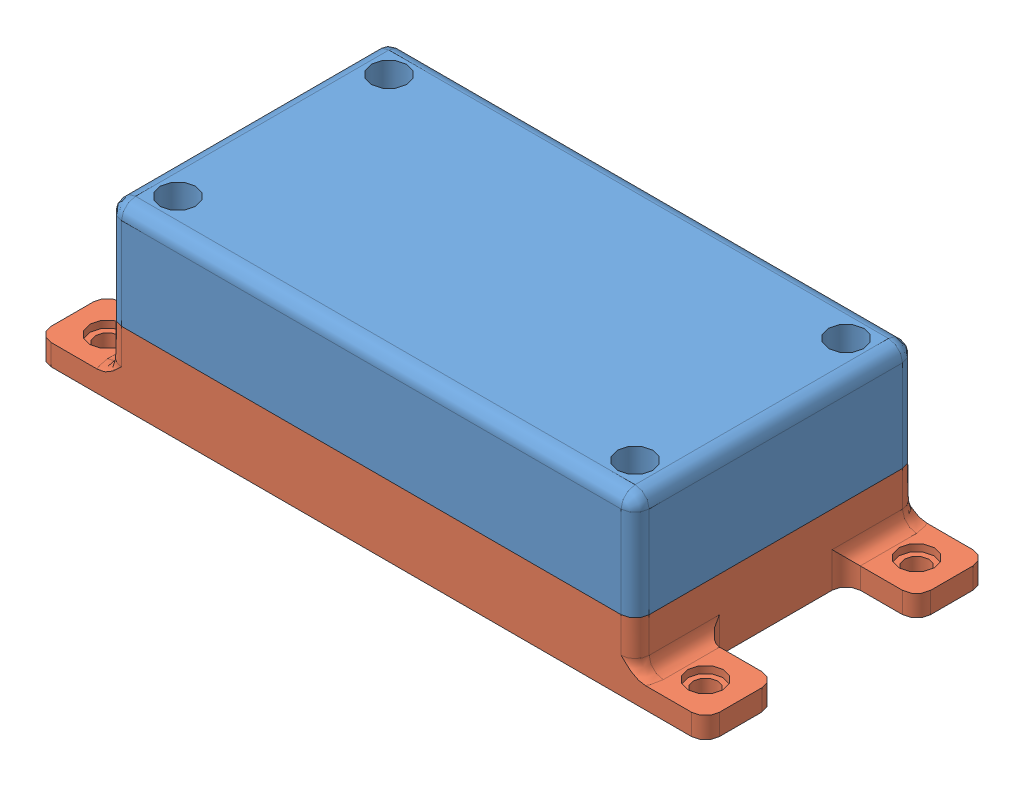
SolidWorks assembly Assem2, configuration Default. Lengths in mm.
Overall size (95 25 40).
2 component instances, 2 part files, 3 mates.
Components (placement in the parent):
- top2-1: top2 [Default] at (7.5654 63.0707 73.8729) x (1 0 0) z (0 0 -1) size (75 15 40)
- bottom-1: bottom [Default] at (7.5654 38.0707 73.8729) size (95 12 40)
Mates (geometry in assembly coordinates):
- Coincident1: coincident anti-aligned: plane of top2-1 through (7.5654 48.0707 73.8729) normal (0 -1 0); plane of bottom-1 through (7.5654 48.0707 73.8729) normal (0 1 0)
- Concentric1: concentric aligned: cylinder of top2-1 through (40.0654 63.0707 88.8729) axis (0 -1 0) radius 1.7; cylinder of bottom-1 through (40.0654 50.0707 88.8729) axis (0 -1 0) radius 2
- Concentric2: concentric aligned: cylinder of top2-1 through (-24.9346 63.0707 58.8729) axis (0 -1 0) radius 1.7; cylinder of bottom-1 through (-24.9346 50.0707 58.8729) axis (0 -1 0) radius 2
